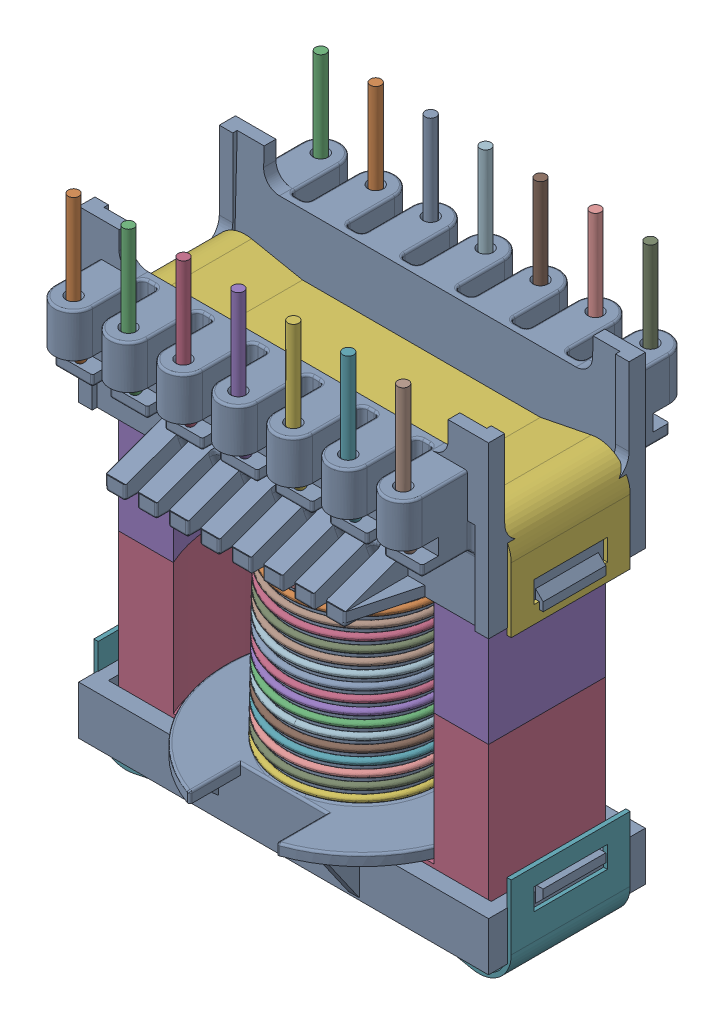
SolidWorks assembly User_Library-ETD34-17-11_Vertical_Bobbin_Part_No._FD9640, configuration Default. Lengths in mm.
Overall size (39.3 49.7 26.36).
20 component instances, 5 part files, 0 mates.
Components (placement in the parent):
- User_Library-ETD34-17-11_Vertical_Bobbin_Part_No._FD9640_FD9640-1: User_Library-ETD34-17-11_Vertical_Bobbin_Part_No._FD9640_FD9640 [Default] at origin size (39.3 42.6 26.36)
- User_Library-ETD34-17-11_Vertical_Bobbin_Part_No._FD9640_1MM_RND_PIN-1: User_Library-ETD34-17-11_Vertical_Bobbin_Part_No._FD9640_1MM_RND_PIN [Default] at origin size (1 13.75 1.63)
- User_Library-ETD34-17-11_Vertical_Bobbin_Part_No._FD9640_1MM_RND_PIN-2: User_Library-ETD34-17-11_Vertical_Bobbin_Part_No._FD9640_1MM_RND_PIN [Default] at (5.08 0 0) size (1 13.75 1.63)
- User_Library-ETD34-17-11_Vertical_Bobbin_Part_No._FD9640_1MM_RND_PIN-3: User_Library-ETD34-17-11_Vertical_Bobbin_Part_No._FD9640_1MM_RND_PIN [Default] at (10.16 0 0) size (1 13.75 1.63)
- User_Library-ETD34-17-11_Vertical_Bobbin_Part_No._FD9640_1MM_RND_PIN-4: User_Library-ETD34-17-11_Vertical_Bobbin_Part_No._FD9640_1MM_RND_PIN [Default] at (15.24 0 0) size (1 13.75 1.63)
- User_Library-ETD34-17-11_Vertical_Bobbin_Part_No._FD9640_1MM_RND_PIN-5: User_Library-ETD34-17-11_Vertical_Bobbin_Part_No._FD9640_1MM_RND_PIN [Default] at (20.32 0 0) size (1 13.75 1.63)
- User_Library-ETD34-17-11_Vertical_Bobbin_Part_No._FD9640_1MM_RND_PIN-6: User_Library-ETD34-17-11_Vertical_Bobbin_Part_No._FD9640_1MM_RND_PIN [Default] at (25.4 0 0) size (1 13.75 1.63)
- User_Library-ETD34-17-11_Vertical_Bobbin_Part_No._FD9640_1MM_RND_PIN-7: User_Library-ETD34-17-11_Vertical_Bobbin_Part_No._FD9640_1MM_RND_PIN [Default] at (30.48 0 0) size (1 13.75 1.63)
- User_Library-ETD34-17-11_Vertical_Bobbin_Part_No._FD9640_1MM_RND_PIN-8: User_Library-ETD34-17-11_Vertical_Bobbin_Part_No._FD9640_1MM_RND_PIN [Default] x (-1 0 0) z (0 0 -1) size (1 13.75 1.63)
- User_Library-ETD34-17-11_Vertical_Bobbin_Part_No._FD9640_1MM_RND_PIN-9: User_Library-ETD34-17-11_Vertical_Bobbin_Part_No._FD9640_1MM_RND_PIN [Default] at (-5.08 0 0) x (-1 0 0) z (0 0 -1) size (1 13.75 1.63)
- User_Library-ETD34-17-11_Vertical_Bobbin_Part_No._FD9640_1MM_RND_PIN-10: User_Library-ETD34-17-11_Vertical_Bobbin_Part_No._FD9640_1MM_RND_PIN [Default] at (-10.16 0 0) x (-1 0 0) z (0 0 -1) size (1 13.75 1.63)
- User_Library-ETD34-17-11_Vertical_Bobbin_Part_No._FD9640_1MM_RND_PIN-11: User_Library-ETD34-17-11_Vertical_Bobbin_Part_No._FD9640_1MM_RND_PIN [Default] at (-15.24 0 0) x (-1 0 0) z (0 0 -1) size (1 13.75 1.63)
- User_Library-ETD34-17-11_Vertical_Bobbin_Part_No._FD9640_1MM_RND_PIN-12: User_Library-ETD34-17-11_Vertical_Bobbin_Part_No._FD9640_1MM_RND_PIN [Default] at (-20.32 0 0) x (-1 0 0) z (0 0 -1) size (1 13.75 1.63)
- User_Library-ETD34-17-11_Vertical_Bobbin_Part_No._FD9640_1MM_RND_PIN-13: User_Library-ETD34-17-11_Vertical_Bobbin_Part_No._FD9640_1MM_RND_PIN [Default] at (-25.4 0 0) x (-1 0 0) z (0 0 -1) size (1 13.75 1.63)
- User_Library-ETD34-17-11_Vertical_Bobbin_Part_No._FD9640_1MM_RND_PIN-14: User_Library-ETD34-17-11_Vertical_Bobbin_Part_No._FD9640_1MM_RND_PIN [Default] at (-30.48 0 0) x (-1 0 0) z (0 0 -1) size (1 13.75 1.63)
- User_Library-ETD34-17-11_Vertical_Bobbin_Part_No._FD9640_ETD34_CORE-1: User_Library-ETD34-17-11_Vertical_Bobbin_Part_No._FD9640_ETD34_CORE [Default] at (0 -16.7 0) size (34.2 17.3 10.8)
- User_Library-ETD34-17-11_Vertical_Bobbin_Part_No._FD9640_ETD34_CORE-2: User_Library-ETD34-17-11_Vertical_Bobbin_Part_No._FD9640_ETD34_CORE [Default] at (0 17.9 0) x (-1 0 0) z (0 0 1) size (34.2 17.3 10.8)
- User_Library-ETD34-17-11_Vertical_Bobbin_Part_No._FD9640_ETD34_CORE_CLIP-1: User_Library-ETD34-17-11_Vertical_Bobbin_Part_No._FD9640_ETD34_CORE_CLIP [Default] at (0 10.3 -5.5) x (0 -1 0) z (-1 0 0) size (9 11 38.6)
- User_Library-ETD34-17-11_Vertical_Bobbin_Part_No._FD9640_ETD34_CORE_CLIP-2: User_Library-ETD34-17-11_Vertical_Bobbin_Part_No._FD9640_ETD34_CORE_CLIP [Default] at (0 -9.1 5.5) x (0 1 0) z (-1 0 0) size (9 11 38.6)
- User_Library-ETD34-17-11_Vertical_Bobbin_Part_No._FD9640_ETD34_WINDING-1: User_Library-ETD34-17-11_Vertical_Bobbin_Part_No._FD9640_ETD34_WINDING [Default] at (0.2458 10.0424 -0.0108) x (-0.015539 -0.999863 0.005636) z (0.990175 -0.016171 -0.138898) size (20.6 14.6 14.6)
